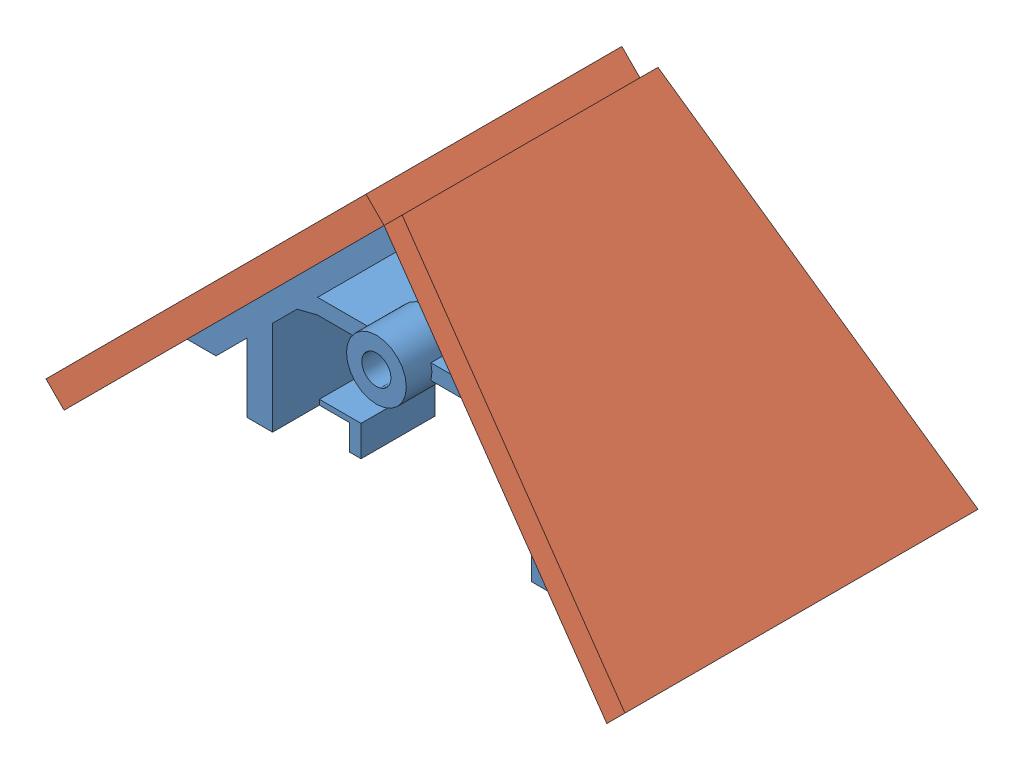
SolidWorks assembly mirror_subasm, configuration Default. Lengths in mm.
Overall size (113.14 57.93 69).
3 component instances, 2 part files, 6 mates.
Components (placement in the parent):
- mirror_mount-1: mirror_mount [new] at origin size (84 54.39 48)
- mirror-1: mirror [Default] x (0.707107 -0.707107 0) z (0 0 1) size (75 5 69)
- mirror-2: mirror [Default] x (-0.707107 -0.707107 0) z (0 0 -1) size (75 5 69)
Mates (geometry in assembly coordinates):
- Coincident1: coincident anti-aligned: plane of mirror_mount-1 through (0 0 21.5) normal (-0.707107 0.707107 0); plane of mirror-2 through (0 0 0) normal (0.707107 -0.707107 0)
- Coincident2: coincident anti-aligned: plane of mirror_mount-1 through (0 0 21.5) normal (0.707107 0.707107 0); plane of mirror-1 through (0 0 0) normal (-0.707107 -0.707107 0)
- Coincident9: coincident: point of mirror_mount-1; unknown of mirror-2
- Coincident5: coincident: unknown of mirror_mount-1; unknown of mirror-1
- Coincident6: coincident aligned: line of mirror_mount-1 through (0 0 21.5) axis (0 0 -1); line of mirror-2 through (0 0 25) axis (0 0 -1)
- Coincident7: coincident anti-aligned: line of mirror_mount-1 through (0 0 21.5) axis (0 0 -1); line of mirror-1 through (0 0 -25) axis (0 0 1)
